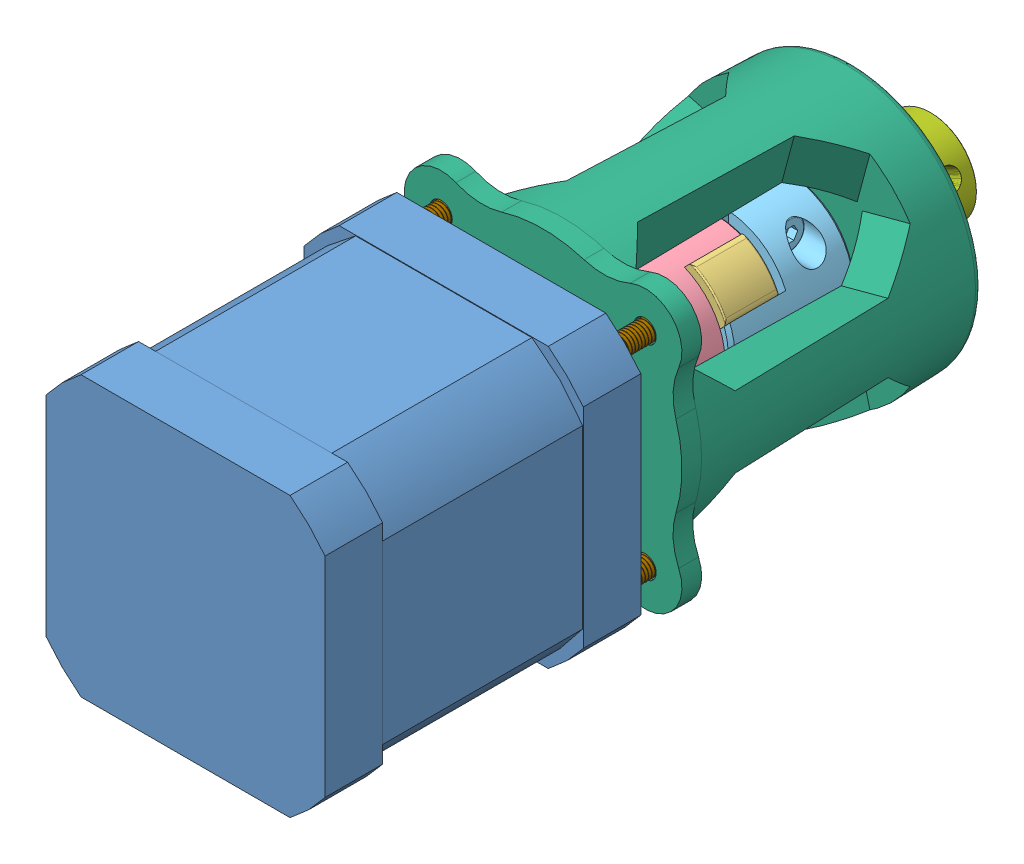
SolidWorks assembly z-motor_thrust_assembly, configuration Default. Lengths in mm.
Overall size (42.42 42.42 113.35).
16 component instances, 9 part files, 25 mates.
Components (placement in the parent):
- 17HM19-2004S-1: 17HM19-2004S [Default] at (0 -11.5 6.35) x (1 0 0) z (0 0 -1) size (42.42 42.42 72)
- AST_Bearings_F8-19M-1: AST_Bearings_F8-19M [Default] at (-0.0375 -11.4625 -48.5) x (1 0 0) z (0 1 0) size (19 7 19)
- couplings_cajc20-rd-5-8-1: couplings_cajc20-rd-5-8 [Default] at (0 -11.5 -22.65) x (0 0 -1) z (1 0 0) size (30 20 20)
  - couplings_cajc20-rd-5-8_01-1: couplings_cajc20-rd-5-8_01 [Default] at origin size (8 18.12 18.12)
  - couplings_cajc20-rd-5-8_02-1: couplings_cajc20-rd-5-8_02 [Default] at origin size (19 20 19.99)
  - couplings_cajc20-rd-5-8_03-1: couplings_cajc20-rd-5-8_03 [Default] at origin size (19 19.99 20)
- thrust_cage-1: thrust_cage [Default] at (-0.0375 -11.4625 -15.6528) x (1 0 0) z (0 1 0) size (42.3 47 42.3)
- T8_lock_collar-1: T8_lock_collar [Default] at (-0.0375 -11.4625 -59) x (0 1 0) z (1 0 0) size (14 7 14)
- m3_stainless_steel_washer_90965A130-1: m3_stainless_steel_washer_90965A130 [90965A130] at (15.5 4 -3) x (0.923728 0.383049 0) z (0 0 -1) size (7 7 0.6)
- m3_12mm_buttohead_screw_92095A183-1: m3_12mm_buttohead_screw_92095A183 [92095A183] at (15.5 4 -5.25) x (0.923728 0.383049 0) z (0 0 -1) size (5.7 5.7 13.97)
- m3_stainless_steel_washer_90965A130-2: m3_stainless_steel_washer_90965A130 [90965A130] at (-15.5 4 -3) x (0.923728 0.383049 0) z (0 0 -1) size (7 7 0.6)
- m3_stainless_steel_washer_90965A130-3: m3_stainless_steel_washer_90965A130 [90965A130] at (15.5 -27 -3) x (0.923728 0.383049 0) z (0 0 -1) size (7 7 0.6)
- m3_stainless_steel_washer_90965A130-4: m3_stainless_steel_washer_90965A130 [90965A130] at (-15.5 -27 -3) x (0.923728 0.383049 0) z (0 0 -1) size (7 7 0.6)
- m3_12mm_buttohead_screw_92095A183-2: m3_12mm_buttohead_screw_92095A183 [92095A183] at (15.5 -27 -5.25) x (0.923728 0.383049 0) z (0 0 -1) size (5.7 5.7 13.97)
- m3_12mm_buttohead_screw_92095A183-3: m3_12mm_buttohead_screw_92095A183 [92095A183] at (-15.5 -27 -5.25) x (0.923728 0.383049 0) z (0 0 -1) size (5.7 5.7 13.97)
- m3_12mm_buttohead_screw_92095A183-5: m3_12mm_buttohead_screw_92095A183 [92095A183] at (-15.5 4 -5.25) x (0.923728 0.383049 0) z (0 0 -1) size (5.7 5.7 13.97)
Mates (geometry in assembly coordinates):
- Coincident3: coincident aligned: plane of 17HM19-2004S-1 through (0 -11.5 -17.65) normal (0 0 -1); plane of couplings_cajc20-rd-5-8-1/couplings_cajc20-rd-5-8_02-1 through (0 -6.5 -17.65) normal (0 0 -1)
- Concentric4: concentric aligned: cylinder of 17HM19-2004S-1 through (0 -11.5 -17.65) axis (0 0 1) radius 2.5; cylinder of couplings_cajc20-rd-5-8-1/couplings_cajc20-rd-5-8_02-1 through (0 -11.5 -10.2) axis (0 0 1) radius 2.5
- Concentric1: concentric aligned: cylinder of AST_Bearings_F8-19M-1 through (-0.0375 -11.4625 -52.35) axis (0 0 1) radius 9.5; cylinder of thrust_cage-1 through (-0.0375 -11.4625 584.9462) axis (0 0 1) radius 9.7
- Coincident1: coincident anti-aligned: plane of AST_Bearings_F8-19M-1 through (-0.0375 -11.4625 -45) normal (0 0 1); plane of thrust_cage-1 through (-0.0375 -11.4625 -45) normal (0 0 -1)
- Concentric6: concentric anti-aligned: cylinder of AST_Bearings_F8-19M-1 through (-0.0375 -11.4625 -52.35) axis (0 0 1) radius 9.4; cylinder of T8_lock_collar-1 through (-0.0375 -11.4625 -52) axis (0 0 -1) radius 7
- Coincident5: coincident anti-aligned: plane of AST_Bearings_F8-19M-1 through (-0.0375 -11.4625 -52) normal (0 0 -1); plane of T8_lock_collar-1 through (-0.0375 -11.4625 -52) normal (0 0 1)
- Distance1: distance = 6.35 mm anti-aligned: plane of 17HM19-2004S-1 through (0 -11.5 6.35) normal (0 0 -1); plane of thrust_cage-1 through (-0.0375 -11.4625 0) normal (0 0 1)
- Concentric7: concentric aligned: cylinder of 17HM19-2004S-1 through (15.5 4 6.35) axis (0 0 -1) radius 1.5; cylinder of thrust_cage-1 through (15.5 4 -3) axis (0 0 -1) radius 1.7
- Concentric8: concentric aligned: cylinder of 17HM19-2004S-1 through (-15.5 -27 6.35) axis (0 0 -1) radius 1.5; cylinder of thrust_cage-1 through (-15.5 -27 -3) axis (0 0 -1) radius 1.7
- Concentric101: concentric anti-aligned: cylinder of thrust_cage-1 through (15.5 4 -3) axis (0 0 -1) radius 1.7; cylinder of m3_stainless_steel_washer_90965A130-1 through (15.5 4 -3.6) axis (0 0 1) radius 3.5
- Coincident81: coincident anti-aligned: plane of thrust_cage-1 through (-0.0375 -11.4625 -3) normal (0 0 -1); plane of m3_stainless_steel_washer_90965A130-1 through (15.5 4 -3) normal (0 0 1)
- Concentric111: concentric anti-aligned: cylinder of m3_stainless_steel_washer_90965A130-1 through (15.5 4 -3.6) axis (0 0 1) radius 3.5; cylinder of m3_12mm_buttohead_screw_92095A183-1 through (15.5 4 -5.25) axis (0 0 -1) radius 2.85
- Coincident91: coincident anti-aligned: plane of m3_stainless_steel_washer_90965A130-1 through (15.5 4 -3.6) normal (0 0 -1); plane of m3_12mm_buttohead_screw_92095A183-1 through (14.4083 6.6326 -3.6) normal (0 0 1)
- Concentric121: concentric anti-aligned: cylinder of thrust_cage-1 through (-15.5 4 -3) axis (0 0 -1) radius 1.7; cylinder of m3_stainless_steel_washer_90965A130-2 through (-15.5 4 -3.6) axis (0 0 1) radius 3.5
- Coincident101: coincident anti-aligned: plane of thrust_cage-1 through (-0.0375 -11.4625 -3) normal (0 0 -1); plane of m3_stainless_steel_washer_90965A130-2 through (-15.5 4 -3) normal (0 0 1)
- Concentric131: concentric anti-aligned: cylinder of thrust_cage-1 through (15.5 -27 -3) axis (0 0 -1) radius 1.7; cylinder of m3_stainless_steel_washer_90965A130-3 through (15.5 -27 -3.6) axis (0 0 1) radius 3.5
- Coincident111: coincident anti-aligned: plane of thrust_cage-1 through (-0.0375 -11.4625 -3) normal (0 0 -1); plane of m3_stainless_steel_washer_90965A130-3 through (15.5 -27 -3) normal (0 0 1)
- Concentric141: concentric anti-aligned: cylinder of thrust_cage-1 through (-15.5 -27 -3) axis (0 0 -1) radius 1.7; cylinder of m3_stainless_steel_washer_90965A130-4 through (-15.5 -27 -3.6) axis (0 0 1) radius 3.5
- Coincident121: coincident anti-aligned: plane of thrust_cage-1 through (-0.0375 -11.4625 -3) normal (0 0 -1); plane of m3_stainless_steel_washer_90965A130-4 through (-15.5 -27 -3) normal (0 0 1)
- Concentric151: concentric anti-aligned: cylinder of m3_stainless_steel_washer_90965A130-3 through (15.5 -27 -3.6) axis (0 0 1) radius 1.6; cylinder of m3_12mm_buttohead_screw_92095A183-2 through (15.5 -27 -5.25) axis (0 0 -1) radius 2.85
- Coincident131: coincident anti-aligned: plane of m3_stainless_steel_washer_90965A130-3 through (15.5 -27 -3.6) normal (0 0 -1); plane of m3_12mm_buttohead_screw_92095A183-2 through (14.4083 -24.3674 -3.6) normal (0 0 1)
- Concentric161: concentric anti-aligned: cylinder of m3_stainless_steel_washer_90965A130-4 through (-15.5 -27 -3.6) axis (0 0 1) radius 1.6; cylinder of m3_12mm_buttohead_screw_92095A183-3 through (-15.5 -27 -5.25) axis (0 0 -1) radius 2.85
- Coincident141: coincident anti-aligned: plane of m3_stainless_steel_washer_90965A130-4 through (-15.5 -27 -3.6) normal (0 0 -1); plane of m3_12mm_buttohead_screw_92095A183-3 through (-16.5917 -24.3674 -3.6) normal (0 0 1)
- Concentric181: concentric anti-aligned: cylinder of m3_stainless_steel_washer_90965A130-2 through (-15.5 4 -3.6) axis (0 0 1) radius 3.5; cylinder of m3_12mm_buttohead_screw_92095A183-5 through (-15.5 4 -5.25) axis (0 0 -1) radius 2.85
- Coincident161: coincident anti-aligned: plane of m3_stainless_steel_washer_90965A130-2 through (-15.5 4 -3.6) normal (0 0 -1); plane of m3_12mm_buttohead_screw_92095A183-5 through (-16.5917 6.6326 -3.6) normal (0 0 1)
